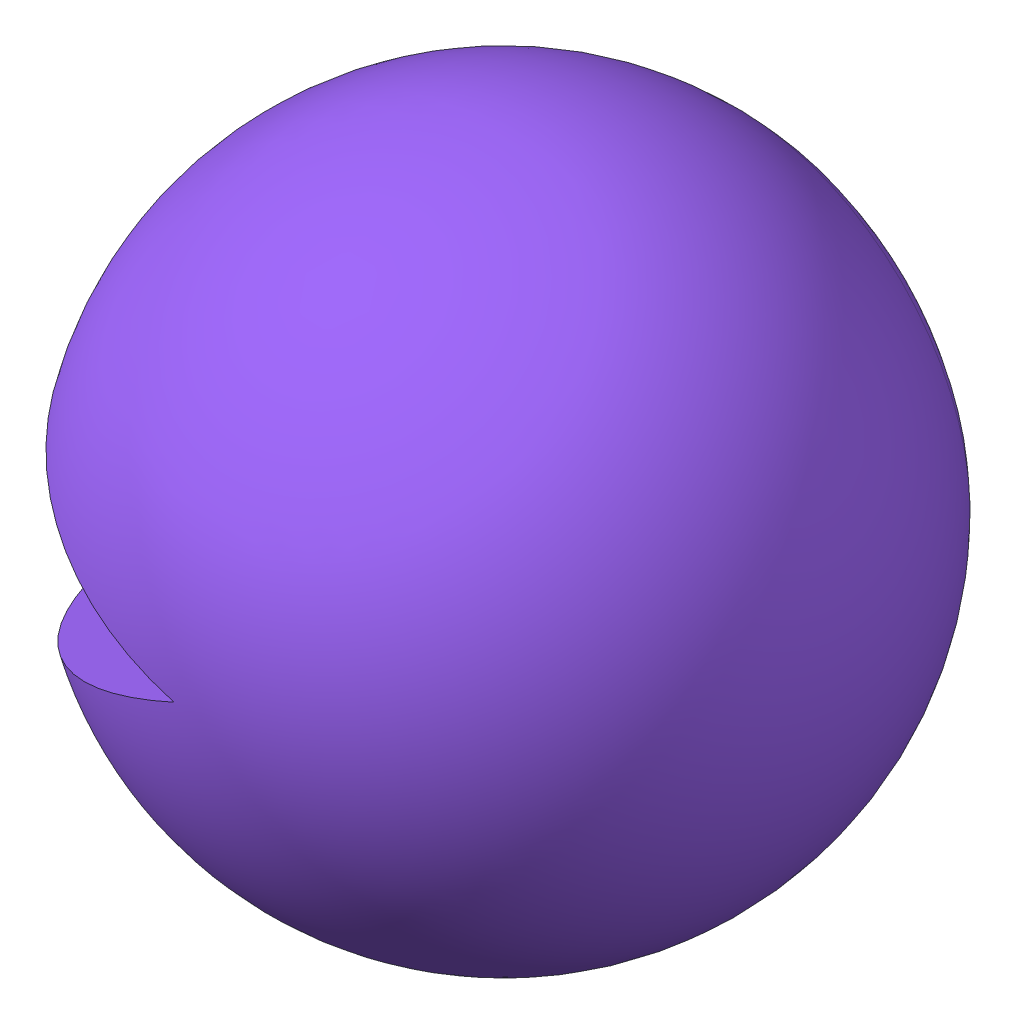
SolidWorks assembly GR6100-2700 机器人数模（L侧）-2016 V1.0, configuration 默认. Lengths in mm.
Overall size (5411.83 5489.61 5055.11).
8 component instances, 8 part files, 27 mates.
Components (placement in the parent):
- 复件 底座^GR6100-2700 机器人数模（L侧）-2016 V1.0-3: 复件 底座^GR6100-2700 机器人数模（L侧）-2016 V1.0 [默认] at (-75.5764 34.0027 647.3326) x (-1 0 0) z (0 1 0) size (675 510 660) (virtual)
- 复件 转座^GR6100-2700 机器人数模（L侧）-2016 V1.0-1: 复件 转座^GR6100-2700 机器人数模（L侧）-2016 V1.0 [默认] at (-65.5435 35.1938 562.2241) x (-1 0 0) z (0 1 0) size (539.78 673.77 602.58) (virtual)
- 复件 大臂^GR6100-2700 机器人数模（L侧）-2016 V1.0-1: 复件 大臂^GR6100-2700 机器人数模（L侧）-2016 V1.0 [默认] at (-65.5435 35.1938 562.2241) x (-1 0 0) z (0 1 0) size (480 1380 306.5) (virtual)
- 复件 工艺臂^GR6100-2700 机器人数模（L侧）-2016 V1.0-3: 复件 工艺臂^GR6100-2700 机器人数模（L侧）-2016 V1.0 [默认] at (495.9249 -17.4507 1782.6828) x (-1 0 0) z (0 1 0) size (2046.33 387.05 459.55) (virtual)
- 复件 J4^GR6100-2700 机器人数模（L侧）-2016 V1.0-1: 复件 J4^GR6100-2700 机器人数模（L侧）-2016 V1.0 [默认] at (2022.2546 -14.6125 1800) size (109.88 115.37 150.27) (virtual)
- 复件 J5^GR6100-2700 机器人数模（L侧）-2016 V1.0-1: 复件 J5^GR6100-2700 机器人数模（L侧）-2016 V1.0 [默认] at (1325.7454 287.6125 1800) x (-1 0 0) z (0 0 1) size (138.45 83.45 96.45) (virtual)
- 复件 法兰^GR6100-2700 机器人数模（L侧）-2016 V1.0-1: 复件 法兰^GR6100-2700 机器人数模（L侧）-2016 V1.0 [默认] at (1778.75 136.5 1663.5) x (-1 0 0) z (0 0.5 -0.866025) size (13 60 60) (virtual)
- 复件 运动范围图^GR6100-2700 机器人数模（L侧）-2016 V1.0-2: 复件 运动范围图^GR6100-2700 机器人数模（L侧）-2016 V1.0 [默认] at (0 0 800) x (-0.999628 0.027259 0) z (0.027259 0.999628 0) size (5268.01 5055.11 5348) (virtual)
Mates (geometry in assembly coordinates):
- 重合1: coincident: line of 复件 底座^GR6100-2700 机器人数模（L侧）-2016 V1.0-3 through (0 0 326.5) axis (0 0 -1); plane of assembly
- 重合2: coincident: line of 复件 底座^GR6100-2700 机器人数模（L侧）-2016 V1.0-3 through (0 0 326.5) axis (0 0 -1); plane of assembly
- 重合3: coincident anti-aligned: plane of 复件 底座^GR6100-2700 机器人数模（L侧）-2016 V1.0-3 through (200 258.1628 0) normal (0 0 -1); plane of assembly through (0 0 0) normal (0 0 1)
- 同心1: concentric aligned: cylinder of 复件 底座^GR6100-2700 机器人数模（L侧）-2016 V1.0-3 through (0 0 448) axis (0 0 -1) radius 180; cylinder of 复件 转座^GR6100-2700 机器人数模（L侧）-2016 V1.0-1 through (0 0 450) axis (0 0 -1) radius 225
- LimitAngle1: limit planar angle = 0 rad aligned: plane of 复件 转座^GR6100-2700 机器人数模（L侧）-2016 V1.0-1 through (-4 -217.5 425) normal (1 0 0); plane of 复件 底座^GR6100-2700 机器人数模（L侧）-2016 V1.0-3 through (-4 -224.9644 415.5) normal (1 0 0)
- 距离1: distance = 39.5 mm anti-aligned: plane of 复件 转座^GR6100-2700 机器人数模（L侧）-2016 V1.0-1 through (180 0 430) normal (0 0 -1); plane of 复件 底座^GR6100-2700 机器人数模（L侧）-2016 V1.0-3 through (296.9703 122.602 390.5) normal (0 0 1)
- 转座回归初始位置: coincident aligned: plane of 复件 底座^GR6100-2700 机器人数模（L侧）-2016 V1.0-3 through (-4 -224.9644 415.5) normal (1 0 0); plane of 复件 转座^GR6100-2700 机器人数模（L侧）-2016 V1.0-1 through (-4 -217.5 425) normal (1 0 0)
- 同心2: concentric anti-aligned: cylinder of 复件 转座^GR6100-2700 机器人数模（L侧）-2016 V1.0-1 through (0 1072.3341 800) axis (0 -1 0) radius 255; cylinder of 复件 大臂^GR6100-2700 机器人数模（L侧）-2016 V1.0-1 through (0 -185.6 800) axis (0 1 0) radius 224.75
- LimitAngle2: limit planar angle = 0 rad aligned: plane of 复件 大臂^GR6100-2700 机器人数模（L侧）-2016 V1.0-1 through (4 -195.6 1079.8817) normal (-1 0 0); plane of 复件 转座^GR6100-2700 机器人数模（L侧）-2016 V1.0-1 through (4 -156.85 1083.7716) normal (-1 0 0)
- 距离2: distance = 5 mm anti-aligned: plane of 复件 大臂^GR6100-2700 机器人数模（L侧）-2016 V1.0-1 through (0 -185 800) normal (0 1 0); plane of 复件 转座^GR6100-2700 机器人数模（L侧）-2016 V1.0-1 through (255 -180 455) normal (0 -1 0)
- 大臂回归初始位置: coincident aligned: plane of 复件 转座^GR6100-2700 机器人数模（L侧）-2016 V1.0-1 through (4 -156.85 1083.7716) normal (-1 0 0); plane of 复件 大臂^GR6100-2700 机器人数模（L侧）-2016 V1.0-1 through (4 -195.6 1079.8817) normal (-1 0 0)
- 同心3: concentric aligned: cylinder of 复件 大臂^GR6100-2700 机器人数模（L侧）-2016 V1.0-1 through (0 -379.6 1800) axis (0 1 0) radius 140; cylinder of 复件 工艺臂^GR6100-2700 机器人数模（L侧）-2016 V1.0-3 through (0 -240.625 1800) axis (0 1 0) radius 125
- LimitAngle3: limit planar angle = 0 rad aligned: plane of 复件 大臂^GR6100-2700 机器人数模（L侧）-2016 V1.0-1 through (175.3742 -233.1 1794) normal (0 0 1); plane of 复件 工艺臂^GR6100-2700 机器人数模（L侧）-2016 V1.0-3 through (170 -209 1796) normal (0 0 1)
- 距离3: distance = 4.6 mm anti-aligned: plane of 复件 工艺臂^GR6100-2700 机器人数模（L侧）-2016 V1.0-3 through (141.68 -210 1941.68) normal (0 -1 0); plane of 复件 大臂^GR6100-2700 机器人数模（L侧）-2016 V1.0-1 through (0 -214.6 1940) normal (0 1 0)
- 工艺臂回归初始位置: parallel aligned: plane of 复件 大臂^GR6100-2700 机器人数模（L侧）-2016 V1.0-1 through (175.3742 -233.1 1794) normal (0 0 1); plane of 复件 工艺臂^GR6100-2700 机器人数模（L侧）-2016 V1.0-3 through (170 -209 1796) normal (0 0 1)
- 同心4: concentric aligned: cylinder of 复件 J4^GR6100-2700 机器人数模（L侧）-2016 V1.0-1 through (1674 80.5 1800) axis (0 1 0) radius 50; cylinder of 复件 工艺臂^GR6100-2700 机器人数模（L侧）-2016 V1.0-3 through (1674 -0.486 1800) axis (0 1 0) radius 62.5
- 距离4: distance = 6 mm anti-aligned: plane of 复件 J4^GR6100-2700 机器人数模（L侧）-2016 V1.0-1 through (1719.54 80 1754.46) normal (0 -1 0); plane of 复件 工艺臂^GR6100-2700 机器人数模（L侧）-2016 V1.0-3 through (1729.66 74 1744.34) normal (0 1 0)
- J4回归初始位置: parallel anti-aligned: plane of 复件 J4^GR6100-2700 机器人数模（L侧）-2016 V1.0-1 through (1705.878 168.378 1708.5) normal (0 0 -1); plane of 复件 工艺臂^GR6100-2700 机器人数模（L侧）-2016 V1.0-3 through (1049 -20 1915) normal (0 0 1)
- 同心5: concentric anti-aligned: cylinder of 复件 J4^GR6100-2700 机器人数模（L侧）-2016 V1.0-1 through (1674 136.5 1708.5) axis (0 0 1) radius 31.5; cylinder of 复件 J5^GR6100-2700 机器人数模（L侧）-2016 V1.0-1 through (1674 136.5 1709.75) axis (0 0 -1) radius 29
- 距离5: distance = 2.5 mm anti-aligned: plane of 复件 J5^GR6100-2700 机器人数模（L侧）-2016 V1.0-1 through (1674 136.5 1713.75) normal (0 0 1); plane of 复件 J4^GR6100-2700 机器人数模（L侧）-2016 V1.0-1 through (1714.48 176.9635 1711.25) normal (0 0 -1)
- J5回归初始位置: parallel anti-aligned: plane of 复件 J4^GR6100-2700 机器人数模（L侧）-2016 V1.0-1 through (1672.8548 176.4836 1711.25) normal (0.866025 0.5 0); plane of 复件 J5^GR6100-2700 机器人数模（L侧）-2016 V1.0-1 through (1674 99.25 1699.75) normal (-0.866025 -0.5 0)
- 同心6: concentric anti-aligned: cylinder of 复件 J5^GR6100-2700 机器人数模（L侧）-2016 V1.0-1 through (1751.25 136.5 1663.5) axis (-1 0 0) radius 22.5; cylinder of 复件 法兰^GR6100-2700 机器人数模（L侧）-2016 V1.0-1 through (1778.75 136.5 1663.5) axis (1 0 0) radius 30
- 距离6: distance = 6.5 mm anti-aligned: plane of 复件 法兰^GR6100-2700 机器人数模（L侧）-2016 V1.0-1 through (1765.75 154.2535 1673.75) normal (-1 0 0); plane of 复件 J5^GR6100-2700 机器人数模（L侧）-2016 V1.0-1 through (1759.25 147.9805 1691.2164) normal (1 0 0)
- 法兰回归初始位置: planar angle = 0.261799 rad aligned: plane of 复件 J5^GR6100-2700 机器人数模（L侧）-2016 V1.0-1 through (1741.25 166.871 1663.9452) normal (0 0.5 -0.866025); plane of 复件 法兰^GR6100-2700 机器人数模（L侧）-2016 V1.0-1 through (1698.55 161.1856 1677.7523) normal (0 0.707107 -0.707107)
- 同心7: concentric: sphere of 复件 运动范围图^GR6100-2700 机器人数模（L侧）-2016 V1.0-2; line of 复件 底座^GR6100-2700 机器人数模（L侧）-2016 V1.0-3 through (0 0 326.5) axis (0 0 -1)
- 距离7: distance = 800 mm aligned: plane of 复件 运动范围图^GR6100-2700 机器人数模（L侧）-2016 V1.0-2; plane of 复件 底座^GR6100-2700 机器人数模（L侧）-2016 V1.0-3 through (200 -258.1628 0) normal (0 0 -1)
- 角度1: planar angle = 0.076585 rad aligned: plane of 复件 底座^GR6100-2700 机器人数模（L侧）-2016 V1.0-3 through (-450 -330 0) normal (0 -1 0); plane of 复件 运动范围图^GR6100-2700 机器人数模（L侧）-2016 V1.0-2
